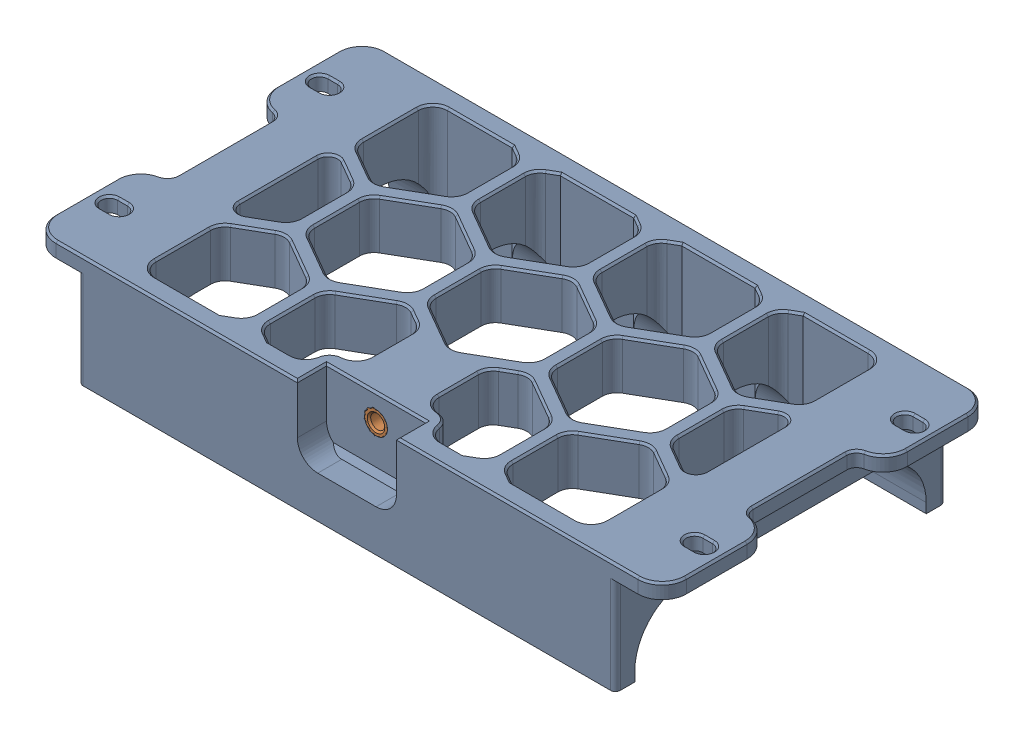
SolidWorks assembly Rear Grill Midsection v13, configuration Default. Lengths in mm.
Overall size (129.8 23 68).
2 component instances, 2 part files, 0 mates.
Components (placement in the parent):
- Rear Grill Midsection v13-1: Rear Grill Midsection v13 [Default] at origin size (129.8 23 68)
- M3 Threaded Insert (6)-1: M3 Threaded Insert (6) [Default] at (1.0892 -365.2198 54.1501) size (5 5 3.85)
